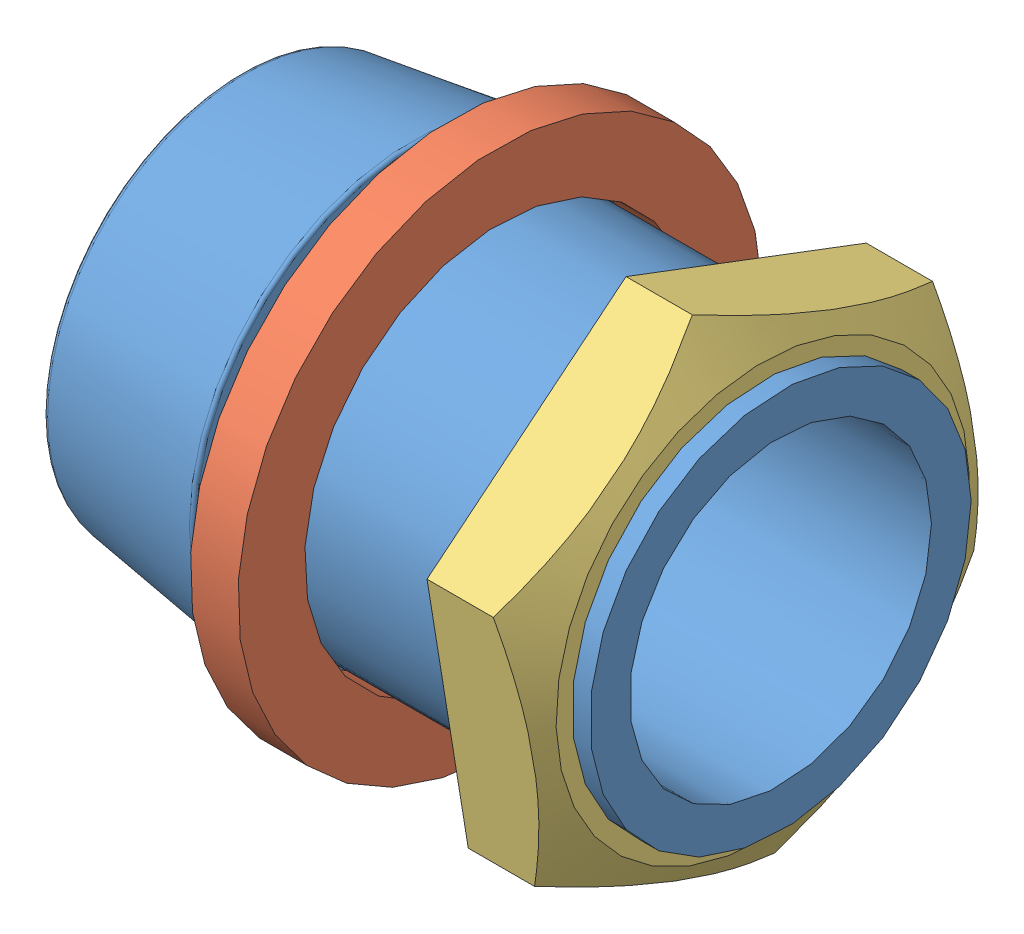
SolidWorks assembly PLH-8 LED holder, configuration Default. Lengths in mm.
Overall size (17 18.82 20.08).
3 component instances, 3 part files, 2 mates.
Components (placement in the parent):
- PLH-8 LED holder - body-1: PLH-8 LED holder - body [Default] at origin size (17 13.97 13.97)
- PLH-8 LED holder - spacer-1: PLH-8 LED holder - spacer [Default] at (6.678 0 0) x (0 -0.067409 -0.997725) z (1 0 0) size (16.5 16.5 1.5)
- PLH-8 LED holder - nut-1: PLH-8 LED holder - nut [Default] at (13.4388 0 0) x (0 -0.935049 0.354519) z (0 0.354519 0.935049) size (14 3 16.17)
Mates (geometry in assembly coordinates):
- Концентричный1: concentric anti-aligned: cylinder of PLH-8 LED holder - body-1 through (0 0 0) axis (1 0 0) radius 6; cylinder of PLH-8 LED holder - spacer-1 through (8.178 0 0) axis (-1 0 0) radius 6.15
- Концентричный2: concentric anti-aligned: cylinder of PLH-8 LED holder - body-1 through (0 0 0) axis (1 0 0) radius 6; cylinder of PLH-8 LED holder - nut-1 through (16.4388 0 0) axis (-1 0 0) radius 5.5
